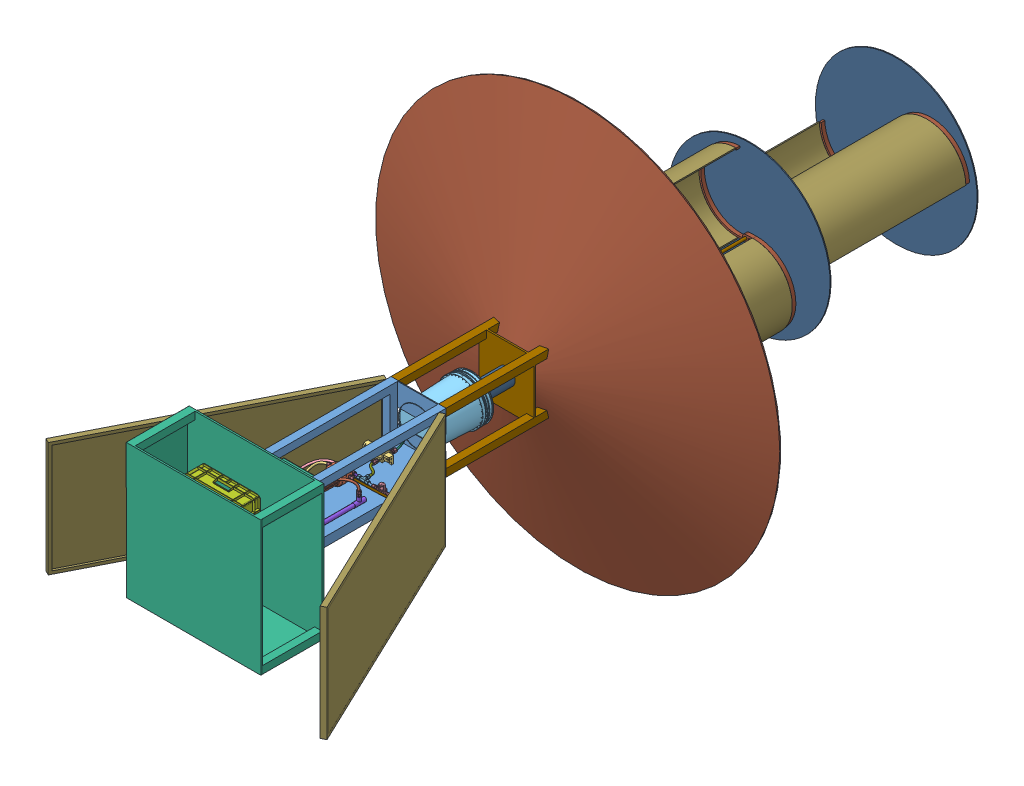
SolidWorks assembly EnertreeAssembly, configuration Default. Lengths in mm.
Overall size (2756.46 2756.46 4848.54).
66 component instances, 37 part files, 29 mates.
Components (placement in the parent):
- Enertree_WaterFiltrationSection-1: Enertree_WaterFiltrationSection [Default] at (-202.4485 -206.6271 -548.4912) size (463.55 762 1117.6)
- Flow-Pur POE12GACB Water Filter-1: Flow-Pur POE12GACB Water Filter [Default] at (-99.0062 -83.9954 183.7168) x (0.999876 0.015543 0.002523) z (-0.015504 0.999773 -0.014582) size (115.89 310.95 115.89)
- Bomba_de_agua_12v_0.50in-1: Bomba_de_agua_12v_0.50in [Predeterminado] at (-112.9905 -110.4717 -372.2477) x (0 0 1) z (-1 0 0) size (93.51 63.61 173.5)
- SELENOID VALVE-1: SELENOID VALVE [Default] at (92.8226 -107.5271 -172.2234) x (1 0 0) z (0 -1 0) size (65 43.5 58.41)
- SELENOID VALVE-2: SELENOID VALVE [Default] at (-158.753 -107.5271 -182.8358) x (1 0 0) z (0 -1 0) size (65 43.5 58.41)
- Bucket-2: Bucket [Default] at (-15.1235 -3.4271 -540.8004) x (0 -1 0) z (1 0 0) size (305.37 370.84 305.37)
- Enertree_PowerStorage-1: Enertree_PowerStorage [Default] at (0 0 569.1088) x (1 0 0) z (0 -1 0) size (916.25 430.37 915.66)
- Storage Bin 50L-1: Storage Bin 50L [Default] at (-27.8384 14.5052 845.1213) x (0 1 0) z (-1 0 0) size (600 273 400)
- UVReactor-1: UVReactor [Default] at (103.0364 -126.9904 343.8722) x (1 0 0) z (0 1 0) size (29.56 406.4 52.88)
- UpperFiltration-Catchment-2: UpperFiltration-Catchment [Default] at (-15.1235 -3.4271 -1158.0912) x (1 0 0) z (0 -1 0) size (374.65 949.2 406.4)
- WaterFiltrationConnection-1: WaterFiltrationConnection [Default] at (-15.1235 -3.4271 -1146.9787) x (0 1 0) z (1 0 0) size (115.67 235.5 115.67)
- CatchmentArea-1: CatchmentArea [Default] at (297.2917 -2.669 -1182.8457) x (0 0 -1) z (0.999997 0.002427 0) size (466.64 2749.8 2749.8)
- advanced solar cell-1: advanced solar cell [Default] at (553.8273 -190.2271 266.326) x (0.430511 0 0.902585) z (0 1 0) size (1710 35 780)
- advanced solar cell-2: advanced solar cell [Default] at (-603.9755 -190.2271 238.3229) x (0.45399 0 -0.891007) z (0 1 0) size (1710 35 780)
- Tube_2-EnertreeAssembly-001-1: Tube_2-EnertreeAssembly-001 [Default] at origin size (982.6 888.63 1169.37)
  - straight fitting-1: straight fitting [.38 TUBE X .25 NPT] at (-15.1235 -3.4271 -554.6866) x (0 0 -1) z (1 0 0) size (39.88 20.16 17.46)
  - straight fitting-2: straight fitting [.50 TUBE X .38 NPT] at (-73.4905 -119.7217 -408.5688) x (0 0 1) z (-1 0 0) size (43.43 25.66 22.23)
  - straight fitting-3: straight fitting [.50 TUBE X .38 NPT] at (-73.4905 -119.7217 -335.9265) x (0 0 -1) z (1 0 0) size (43.43 25.66 22.23)
  - straight fitting-4: straight fitting [.50 TUBE X .38 NPT] at (-129.237 -135.2271 -185.7489) x (-1 0 0) z (0 0.924225 0.381849) size (43.43 25.66 22.23)
  - straight fitting-5: straight fitting [.50 TUBE X .38 NPT] at (-161.8792 -135.2271 -185.7489) size (43.43 25.66 22.23)
  - straight fitting-7: straight fitting [.50 TUBE X .38 NPT] at (122.3386 -135.2271 -175.1366) x (-1 0 0) z (0 0.924225 0.381849) size (43.43 25.66 22.23)
  - straight fitting-8: straight fitting [.50 TUBE X .38 NPT] at (89.6963 -135.2271 -175.1366) size (43.43 25.66 22.23)
  - straight fitting-9: straight fitting [.50 TUBE X .38 NPT] at (-50.9959 -87.4661 -105.2955) x (-0.999876 -0.015543 -0.002523) z (0.002523 -0.316343 0.948641) size (43.43 25.66 22.23)
  - straight fitting-12: straight fitting [.50 TUBE X .38 NPT] at (103.0364 -98.8193 -24.4278) x (0 -1 0) z (0 0 1) size (43.43 25.66 22.23)
  - solidworks-lok tubing branch tee-1: solidworks-lok tubing branch tee [MALE BRANCH TEE-0.500T] at (-22.0044 -135.6532 -180.8023) x (-0.998862 0.047303 0.006057) z (-0.002859 0.067389 -0.997723) size (72.14 22.23 48.9)
  - straight fitting-14: straight fitting [.50 TUBE X .38 NPT] at (-145.4265 -88.934 -105.5338) x (0.999876 0.015543 0.002523) z (-0.002523 -0.00002 0.999997) size (43.43 25.66 22.23)
  - straight fitting-15: straight fitting [.50 TUBE X .38 NPT] at (103.0364 -126.9904 333.9433) x (0 0 -1) z (1 0 0) size (43.43 25.66 22.23)
  - straight fitting-16: straight fitting [.50 TUBE X .38 NPT] at (-11.9327 28.3229 248.8376) x (0 0 1) z (-1 0 0) size (43.43 25.66 22.23)
  - straight fitting-20: straight fitting [.50 TUBE X .38 NPT] at (-431.8 -533.7632 570.2924) x (0 0 -1) z (1 0 0) size (43.43 25.66 22.23)
  - straight fitting-21: straight fitting [.50 TUBE X .38 NPT] at (-431.8 -533.7632 598.7404) x (0 0 1) z (0 1 0) size (43.43 25.66 22.23)
  - Tube-375X010^Tube_2-EnertreeAssembly-001-1: Tube-375X010^Tube_2-EnertreeAssembly-001 [Tube .375in OD X .010in Wall] at (-15.1235 -3.4271 -531.5726) x (0.707107 0.707107 0) z (0 0 1) size (133.03 50.49 102.43) (virtual)
  - Tube-500X010^Tube_2-EnertreeAssembly-001-1: Tube-500X010^Tube_2-EnertreeAssembly-001 [Tube .500in OD X .010in Wall] at (-73.4905 -119.7217 -315.3525) x (0.707107 0.707107 0) z (0 0 1) size (40.87 59.71 121.8) (virtual)
  - Tube-500X010_1^Tube_2-EnertreeAssembly-001-1: Tube-500X010_1^Tube_2-EnertreeAssembly-001 [Tube .500in OD X .010in Wall] at (-108.663 -135.2271 -185.7489) x (0 0.707107 0.707107) z (1 0 0) size (17.34 17.43 73.77) (virtual)
  - Tube-500X010_3^Tube_2-EnertreeAssembly-001-1: Tube-500X010_3^Tube_2-EnertreeAssembly-001 [Tube .500in OD X .010in Wall] at (142.9126 -135.2271 -175.1366) x (0 0.707107 0.707107) z (1 0 0) size (97.39 32.59 291.06) (virtual)
  - Tube-500X010_4^Tube_2-EnertreeAssembly-001-1: Tube-500X010_4^Tube_2-EnertreeAssembly-001 [Tube .500in OD X .010in Wall] at (69.1223 -135.2271 -175.1366) x (0 0.707107 0.707107) z (-1 0 0) size (18.91 16.54 78.24) (virtual)
  - Tube-500X010_6^Tube_2-EnertreeAssembly-001-1: Tube-500X010_6^Tube_2-EnertreeAssembly-001 [Tube .500in OD X .010in Wall] at (103.0364 -78.2453 -24.4278) x (0.707107 0 0.707107) z (0 1 0) size (108.22 270.82 114.09) (virtual)
  - Tube-500X010_7^Tube_2-EnertreeAssembly-001-1: Tube-500X010_7^Tube_2-EnertreeAssembly-001 [Tube .500in OD X .010in Wall] at (-165.9979 -89.2537 -105.5857) x (-0.012775 0.707049 0.707049) z (-0.999876 -0.015543 -0.002523) size (352.82 409.42 356.62) (virtual)
  - Tube-500X010_8^Tube_2-EnertreeAssembly-001-1: Tube-500X010_8^Tube_2-EnertreeAssembly-001 [Tube .500in OD X .010in Wall] at (-182.4532 -135.2271 -185.7489) x (0 0.707107 0.707107) z (-1 0 0) size (269.2 832.82 263.74) (virtual)
  - Tube-500X010_10^Tube_2-EnertreeAssembly-001-1: Tube-500X010_10^Tube_2-EnertreeAssembly-001 [Tube .500in OD X .010in Wall] at (-431.8 -533.7632 590.8664) x (0.707107 0.707107 0) z (0 0 1) size (12.7 12.7 23.81) (virtual)
- Assem1-1: Assem1 [Default] at (-703.2525 1710.9334 903.2665) x (1 0 0) z (0 1 0) size (1969.69 192.8 997.3) (hidden)
  - Soporte-2: Soporte [Default<As Machined>] at origin size (1969.69 156.44 996.3)
  - Modulo-1: Modulo [Default] at (-984.8415 70.658 -497.8638) x (1 0 0) z (0 -0.136407 0.990653) size (1956 55 992)
- Assem1-2: Assem1 [Default] at (2654.6587 1641.4367 893.7915) x (1 0 0) z (0 1 0) size (1969.69 192.8 997.3) (hidden)
  - Soporte-2: Soporte [Default<As Machined>] at origin size (1969.69 156.44 996.3)
  - Modulo-1: Modulo [Default] at (-984.8415 70.658 -497.8638) x (1 0 0) z (0 -0.136407 0.990653) size (1956 55 992)
- WaterDispenseContainer-1: WaterDispenseContainer [Default] at (-11.9327 28.3229 518.3088) x (0 1 0) z (-1 0 0) size (241.3 279.4 266.7)
- WaterDispensingLid-1: WaterDispensingLid [Default] at (-11.9327 148.9729 468.7691) x (1 0 0) z (0 1 0) size (63.96 63.96 61.61)
- Overflow_Mount-1: Overflow_Mount [Default] at (-431.8 -508.4375 569.1088) x (0 1 0) z (1 0 0) size (101.6 11.11 50.8)
- BladeAssem2-2: BladeAssem2 [Default] at (-15.1235 -3.4271 -1697.6912) x (0.999637 0.026951 0) z (-0.026951 0.999637 0) size (1506.44 2306.35 1506.44)
  - Shaft1-1: Shaft1 [Default] at origin size (18 2300 18)
  - EndPlate1-1: EndPlate1 [Default] at (0 100 0) x (0.508329 0 0.861163) z (-0.861163 0 0.508329) size (1100 6.35 1100)
  - Blade1-1: Blade1 [Default] at (0 106.35 0) x (-1 0 0) z (0 0 -1) size (621.5 25 1000)
  - EndPlate1-5: EndPlate1 [Default] at (0 1100 0) x (0.508329 0 0.861163) z (-0.861163 0 0.508329) size (1100 6.35 1100)
  - EndPlate1-6: EndPlate1 [Default] at (0 2100 0) x (0.508329 0 0.861163) z (-0.861163 0 0.508329) size (1100 6.35 1100)
  - Blade1-5: Blade1 [Default] at (0 1075 0) x (-1 0 0) z (0 0 -1) size (621.5 25 1000)
  - Blade1-6: Blade1 [Default] at (0 1106.35 0) x (0 0 -1) z (1 0 0) size (621.5 25 1000)
  - Blade1-7: Blade1 [Default] at (0 2075 0) x (0 0 -1) z (1 0 0) size (621.5 25 1000)
  - blade2-1: blade2 [Default] at (-50 131.35 500) x (0 0 -1) z (1 0 0) size (538 991.22 264.75)
  - blade2-2: blade2 [Default] at (50 131.35 -500) x (0 0 1) z (-1 0 0) size (538 991.22 264.75)
  - blade2-3: blade2 [Default] at (-500 1131.35 -50) size (538 991.22 264.75)
  - blade2-4: blade2 [Default] at (500 1131.35 50) x (-1 0 0) z (0 0 -1) size (538 991.22 264.75)
  - base-1: base [Default] at (106.7453 -200 40.4968) size (478.5 19.05 573.44)
  - generator-1: generator [Default] at (153.8935 -180.95 186.719) size (156.14 101.1 156.14)
  - 1277N61_bigpulley2-1: 1277N61_bigpulley2 [1277N61] at (0 -67.3 0) x (0 0 -1) z (0 1 0) size (96.48 96.48 25.4)
  - 1277N27_smallpulley3-1: 1277N27_smallpulley3 [1277N27] at (153.8935 -55.3755 186.719) x (0 0 -1) z (0 1 0) size (30.18 30.18 27)
  - 7939K571_High-Strength HTD Timing Belt-1: 7939K571_High-Strength HTD Timing Belt [7939K571] at (67.1901 -73.2465 80.0514) x (0.652828 0 0.757506) z (0 -1 0) size (312.79 152.79 9)
Mates (geometry in assembly coordinates):
- Coincident6: coincident anti-aligned: plane of Enertree_WaterFiltrationSection-1 through (-202.4485 -145.8271 -548.4912) normal (0 1 0); plane of Bomba_de_agua_12v_0.50in-1 through (-137.66 -145.8271 -393.4609) normal (0 -1 0)
- Coincident8: coincident anti-aligned: plane of Enertree_WaterFiltrationSection-1 through (-202.4485 -145.8271 -548.4912) normal (0 1 0); plane of SELENOID VALVE-1 through (124.7675 -145.8271 -187.6366) normal (0 -1 0)
- Coincident10: coincident anti-aligned: plane of Enertree_WaterFiltrationSection-1 through (-202.4485 -145.8271 -548.4912) normal (0 1 0); plane of SELENOID VALVE-2 through (-151.8081 -145.8271 -198.2489) normal (0 -1 0)
- Coincident12: coincident: plane of Enertree_WaterFiltrationSection-1 through (-202.4485 -145.8271 -548.4912) normal (0 1 0); moEndPointRef_w of Flow-Pur POE12GACB Water Filter-1
- Concentric1: concentric: sphere of Bucket-2
- Coincident28: coincident: point of Enertree_WaterFiltrationSection-1; point of Assem1^EnertreeAssembly-1/FiltrationConnector-1
- Coincident29: coincident aligned: line of Enertree_WaterFiltrationSection-1 through (-202.4485 -206.6271 -548.4912) axis (1 0 0); line of Assem1^EnertreeAssembly-1/FiltrationConnector-1 through (-202.4485 -206.6271 -548.4912) axis (1 0 0)
- Coincident30: coincident: point of Enertree_PowerStorage-1; point of assembly
- Coincident31: coincident: plane of Enertree_PowerStorage-1 through (0 0 986.6213) normal (0 0 -1); point of Storage Bin 50L-1
- Coincident32: coincident anti-aligned: line of Enertree_WaterFiltrationSection-1 through (172.2015 148.9729 -548.4912) axis (-1 0 0); line of UpperFiltration-Catchment-2 through (121.4015 148.9729 -548.4912) axis (1 0 0)
- Coincident33: coincident anti-aligned: line of Enertree_WaterFiltrationSection-1 through (-151.6485 199.7729 -548.4912) axis (0 -1 0); line of UpperFiltration-Catchment-2 through (-151.6485 148.9729 -548.4912) axis (0 1 0)
- Coincident36: coincident anti-aligned: plane of UpperFiltration-Catchment-2 through (-15.1235 -3.4271 -1146.9787) normal (0 0 1); plane of WaterFiltrationConnection-1 through (-15.1235 -3.4271 -1146.9787) normal (0 0 -1)
- Concentric3: concentric aligned: circle of UpperFiltration-Catchment-2; circle of WaterFiltrationConnection-1
- Concentric5: concentric anti-aligned: circle of UpperFiltration-Catchment-2; circle of CatchmentArea-1
- Coincident48: coincident anti-aligned: plane of Enertree_WaterFiltrationSection-1 through (-202.4485 -206.6271 518.3088) normal (0 0 -1); plane of WaterDispenseContainer-1 through (-11.9327 28.3229 518.3088) normal (0 0 1)
- Coincident53: coincident anti-aligned: plane of Enertree_WaterFiltrationSection-1 through (-202.4485 -206.6271 518.3088) normal (0 0 -1); plane of WaterDispenseContainer-1 through (-11.9327 28.3229 518.3088) normal (0 0 1)
- Coincident54: coincident anti-aligned: plane of Enertree_WaterFiltrationSection-1 through (172.2015 148.9729 518.3088) normal (0 -1 0); plane of WaterDispenseContainer-1 through (-145.2827 148.9729 251.6088) normal (0 1 0)
- Concentric10: concentric aligned: circle of WaterDispensingLid-1
- Coincident57: coincident anti-aligned: plane of WaterDispenseContainer-1 through (-145.2827 148.9729 251.6088) normal (0 1 0); plane of WaterDispensingLid-1 through (-11.9327 148.9729 468.7691) normal (0 -1 0)
- Coincident60: coincident anti-aligned: plane of Enertree_PowerStorage-1 through (0 -457.6375 569.1088) normal (0 -1 0); plane of Overflow_Mount-1 through (-406.4 -457.6375 580.2213) normal (0 1 0)
- Coincident61: coincident: point of Enertree_PowerStorage-1; point of Overflow_Mount-1
- Coincident64: coincident: plane of Enertree_WaterFiltrationSection-1 through (172.2015 -206.6271 -542.4912) normal (1 0 0); line of advanced solar cell-1 through (172.2015 -580.2271 -498.9267) axis (0 1 0)
- Coincident66: coincident: plane of Enertree_WaterFiltrationSection-1 through (-202.4485 -206.6271 -542.4912) normal (-1 0 0); line of advanced solar cell-2 through (-202.4485 199.7729 -516.6778) axis (0 -1 0)
- Coincident77: coincident anti-aligned: plane of UpperFiltration-Catchment-2 through (-15.1235 -3.4271 -1497.6912) normal (0 0 -1); plane of BladeAssem2-1/base-1 through (26.6514 -48.8846 -1497.6912) normal (0 0 1)
- Concentric14: concentric anti-aligned: circle of UpperFiltration-Catchment-2; circle of BladeAssem2-1/Shaft1-1
- Concentric15: concentric anti-aligned: circle of UpperFiltration-Catchment-2; circle of BladeAssem2-2/Shaft1-1
- Coincident79: coincident anti-aligned: plane of UpperFiltration-Catchment-2 through (-15.1235 -3.4271 -1497.6912) normal (0 0 -1); plane of BladeAssem2-2/base-1 through (90.4916 39.932 -1497.6912) normal (0 0 1)
- Coincident80: coincident: line of Enertree_WaterFiltrationSection-1 through (172.2015 199.7729 518.3088) axis (0 0 -1); point of advanced solar cell-1
- Coincident81: coincident: line of Enertree_WaterFiltrationSection-1 through (-202.4485 199.7729 518.3088) axis (0 0 -1); point of advanced solar cell-2
